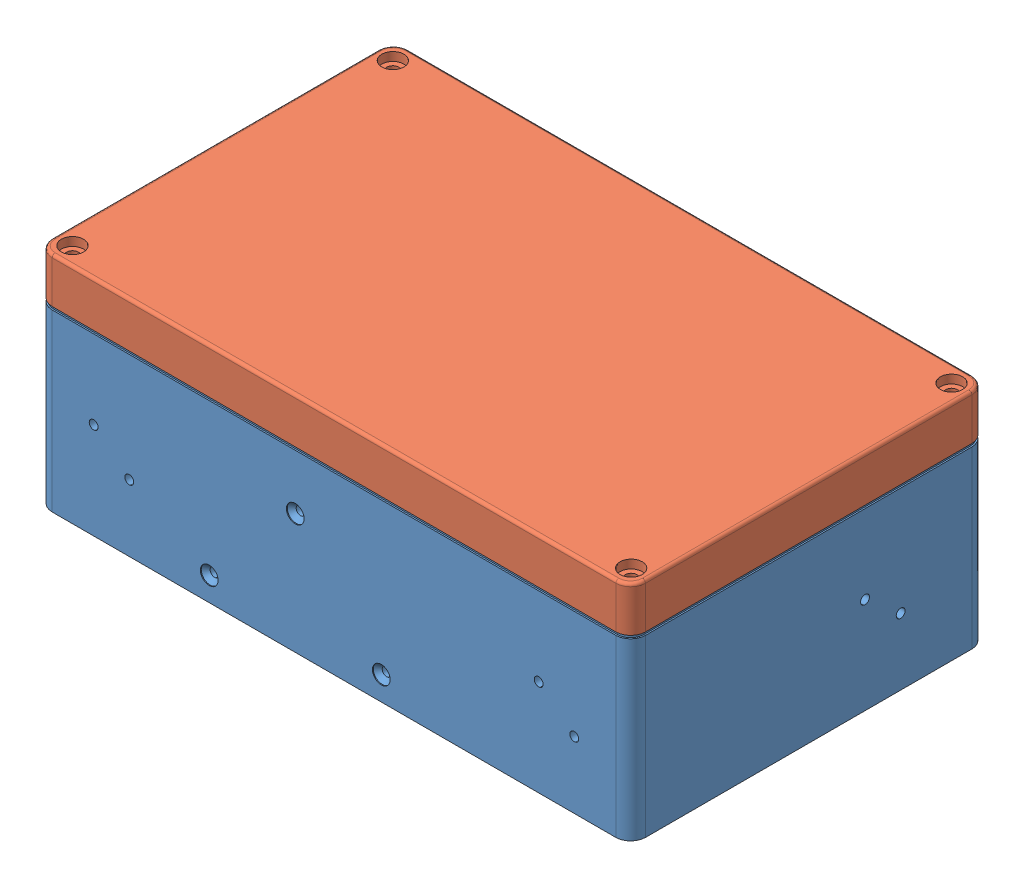
SolidWorks assembly multicomp-G373, configuration Default. Lengths in mm.
Overall size (200 75.2 120).
2 component instances, 2 part files, 4 mates.
Components (placement in the parent):
- multicomp-G373-bottom-1: multicomp-G373-bottom [Modified for robot] at origin size (200 61.55 120)
- multicomp-G373-top-1: multicomp-G373-top [Default] at (0 60 0) x (1 0 0) z (0 1 0) size (200 120 16.2)
Mates (geometry in assembly coordinates):
- InPlace1: in place: plane of multicomp-G373-bottom-1 through (0 60 0) normal (0 1 0); plane of multicomp-G373-top-1 through (0 60 0) normal (0 1 0); moOrthogonalPlaneRef_w of multicomp-G373-bottom-1 through (0 60 0) normal (0 1 0); plane of multicomp-G373-top-1 through (0 60 0) normal (0 0 -1); plane of multicomp-G373-bottom-1 through (0 60 0) normal (0 1 0); plane of multicomp-G373-top-1 through (0 60 0) normal (1 0 0); plane of multicomp-G373-bottom-1 through (0 60 0) normal (0 1 0); unknown of multicomp-G373-top-1
- Coincident1: coincident aligned: plane of multicomp-G373-bottom-1; plane of multicomp-G373-top-1
- Coincident2: coincident aligned: moOrthogonalPlaneRef_w of multicomp-G373-bottom-1 through (0 60 0) normal (0 0 -1); plane of multicomp-G373-top-1 through (0 60 0) normal (0 0 -1)
- Coincident3: coincident anti-aligned: moOrthogonalPlaneRef_w of multicomp-G373-bottom-1 through (0 60 0) normal (-1 0 0); plane of multicomp-G373-top-1 through (0 60 0) normal (1 0 0)
